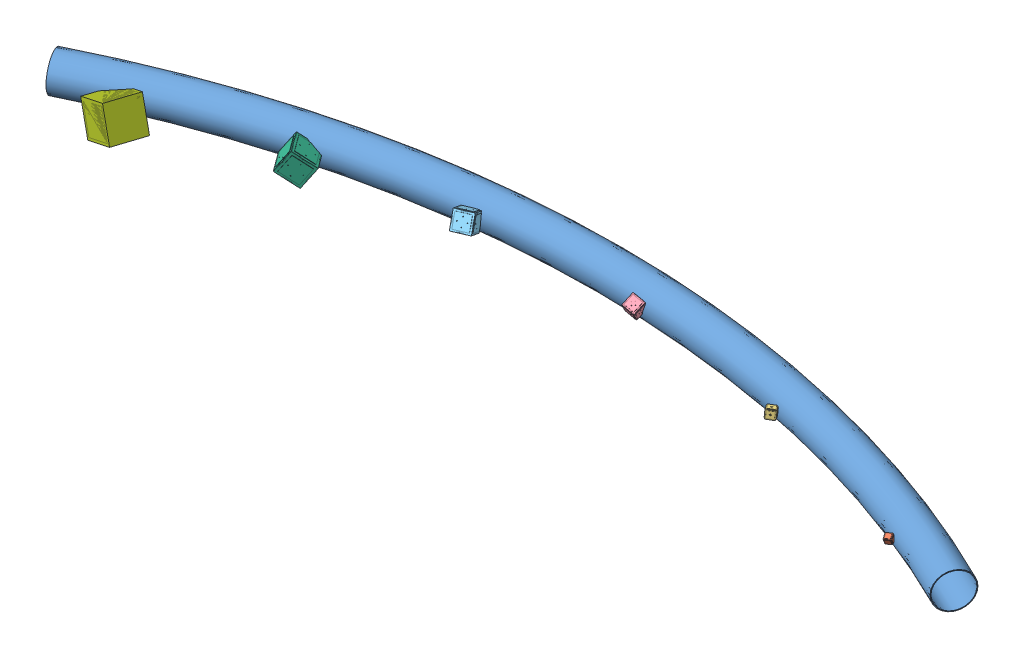
SolidWorks assembly tube2A - with dimensions, configuration Default. Lengths in mm.
Overall size (4303.96 212.13 698.36).
7 component instances, 7 part files, 0 mates.
Components (placement in the parent):
- tubes-1: tubes [tube2A] at origin size (4303.96 168.28 656.76)
- cube_15-2: cube_15 [Default] at (1757.1943 7.1888 -324.7748) x (0.466813 -0.378836 0.799105) z (-0.87943 -0.103618 0.464614) size (31.12 31.12 31.12)
- cube_16-2: cube_16 [Default] at (968.8015 9.4519 -559.7177) x (0.806784 -0.069825 -0.586706) z (0.590423 0.132849 0.796085) size (41.27 41.27 42.23)
- cube_17-2: cube_17 [Default] at (219.4124 11.792 -668.2944) x (0.954748 -0.289413 -0.068523) z (-0.098768 -0.525851 0.844823) size (59.24 59.06 59.06)
- cube_18-2: cube_18 [Default] at (-522.2233 15.3473 -617.0525) x (0.916882 -0.004667 -0.399132) z (0.359767 0.442803 0.821276) size (81.92 81.92 84.87)
- cube_19-2: cube_19 [Default] at (-1183.1884 -5.1426 -489.4193) x (0.660298 -0.557655 -0.503018) z (0.583277 -0.041114 0.811232) size (112.39 112.39 112.56)
- cube_20-2: cube_20 [Default] at (-1812.0839 -23.6863 -257.1651) x (-0.350316 0.927365 -0.131426) z (-0.262185 0.037617 0.964284) size (157.73 157.73 159.27)
